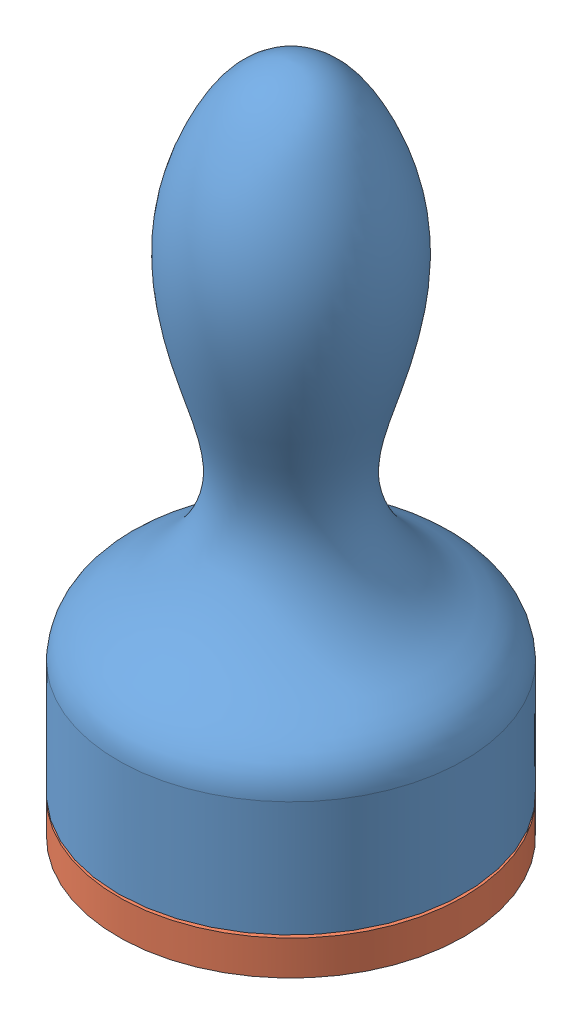
SolidWorks assembly Sello_Completo, configuration Predeterminado. Lengths in mm.
Overall size (39.48 60.23 39.48).
2 component instances, 2 part files, 3 mates.
Components (placement in the parent):
- Mango sello-2: Mango sello [Predeterminado] at (-0.7909 -8.1117 52.4628) size (30 55.5 30)
- Sello_Hoja_LL_20mm-2: Sello_Hoja_LL_20mm [Predeterminado] at (-0.7909 -3.3465 52.4628) x (0.399197 0 -0.916865) z (0.916865 0 0.399197) size (30 10.5 30)
Mates (geometry in assembly coordinates):
- Concéntrica1: concentric: circle of Sello_Hoja_LL_20mm-1; circle of Mango sello-1
- Tornillo1: screw = 1.5 mm aligned: cylinder of Sello_Hoja_LL_20mm-1; cylinder of Mango sello-1 through (-3.7332 18.5373 30) axis (0 -1 0) radius 12
- Concéntrica2: concentric aligned: cylinder of Mango sello-2 through (-0.7909 -3.1117 52.4628) axis (0 -1 0) radius 15; circle of Sello_Hoja_LL_20mm-2
